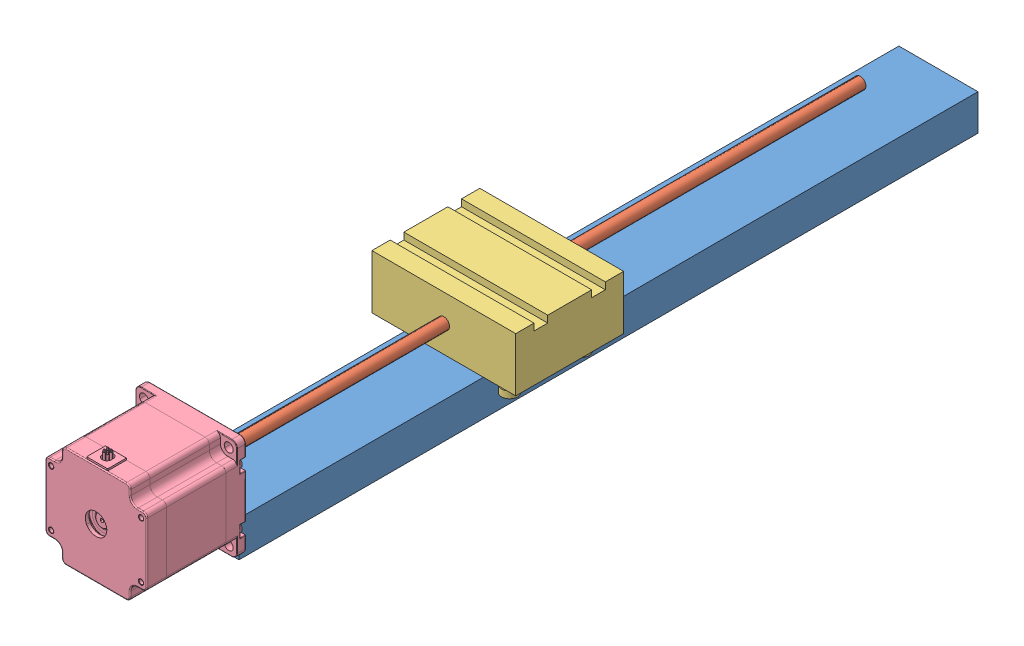
SolidWorks assembly Linear Actuator, configuration Default. Lengths in mm.
Overall size (80 67.6 468.49).
4 component instances, 4 part files, 8 mates.
Components (placement in the parent):
- rail-1: rail [Default] at origin size (44 20 411)
- rod-1: rod [Default] at (21.977 35 -367.5339) x (0.229354 0.973343 0) z (0 0 1) size (6.35 6.35 349.43)
- slider-1: slider [Default] at (-18.023 50 -195.9279) x (0 0 1) z (-1 0 0) size (60 40.16 80)
- stepper motor_NEMA 23-1: stepper motor_NEMA 23 [Default] at (21.977 35 2.4921) x (1 0 0) z (0 0 -1) size (56.41 60.81 75.6)
Mates (geometry in assembly coordinates):
- Coincident5: coordinate: point of rail-1
- Concentric1: concentric aligned: circle of rod-1; cylinder of stepper motor_NEMA 23-1 through (21.977 35 18.0421) axis (0 0 1) radius 0.9
- Coincident10: coincident anti-aligned: plane of rail-1 through (0 20 -411) normal (0 1 0); plane of slider-1 through (-18.023 20 -195.9279) normal (0 -1 0)
- Parallel2: parallel aligned: line of rail-1 through (0 20 -411) axis (0 0 1); line of slider-1 through (-18.023 20 -195.9279) axis (0 0 1)
- Concentric4: concentric anti-aligned: cylinder of rod-1 through (21.977 35 -18.1079) axis (0 0 -1) radius 3.175; cylinder of slider-1 through (21.977 35 -135.9279) axis (0 0 1) radius 2.5527
- Coincident13: coincident anti-aligned: plane of rod-1 through (21.977 35 -18.1079) normal (0 0 1); plane of stepper motor_NEMA 23-1 through (24.552 35 -18.1079) normal (0 0 -1)
- Parallel3: parallel anti-aligned: line of rail-1 through (0 44 0) axis (0 0 1); line of stepper motor_NEMA 23-1 through (47.177 6.8 2.7921) axis (-1 0 0)
- Distance1: distance = 6.223 mm aligned: plane of stepper motor_NEMA 23-1 through (-6.223 18.3 13.4921) normal (-1 0 0); plane of rail-1 through (0 0 -411) normal (-1 0 0)
